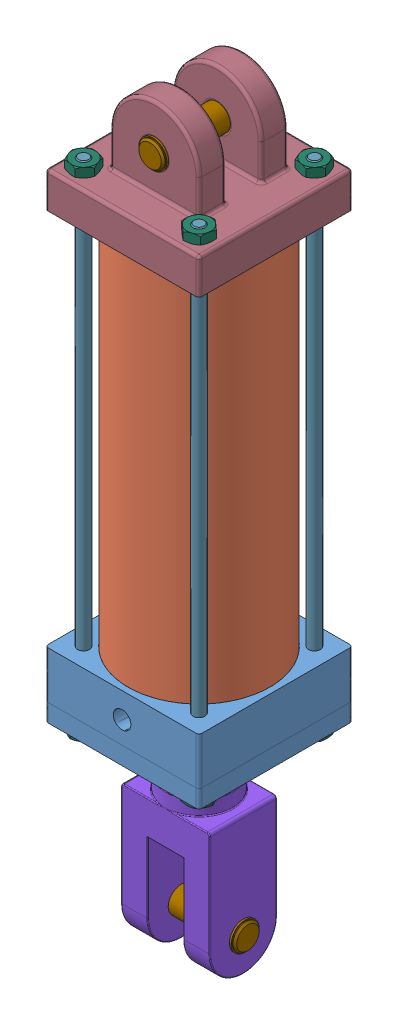
SolidWorks assembly Assem1, configuration Default. Lengths in mm.
Overall size (215.21 810.62 215.21).
28 component instances, 15 part files, 41 mates.
Components (placement in the parent):
- topcover3-2: topcover3 [Default] x (-1 0 0) z (0 1 0) size (165.1 165.1 102.8)
- housingpart-1: housingpart [Default] x (-0.66754 0 0.744574) z (0 1 0) size (152.4 152.4 412)
- backingseal5-1: backingseal5 [Default] at (0 -1 0) x (0 1 0) z (0 0 -1) size (2 152.4 152.4)
- backingseal5-2: backingseal5 [Default] at (0 413 0) x (0 1 0) z (0 0 -1) size (2 152.4 152.4)
- piston seal-1: piston seal [Default] at (0 300.2 0) x (0.999723 0 0.023537) z (0.023537 0 -0.999723) size (146.62 12 146.62)
- piston7-1: piston7 [Default] at (0 318.2 0) x (0 1 0) z (0 0 1) size (57 146.05 146.05)
- pistonrod-1: pistonrod [Default] at (0 -168.8 0) x (0 1 0) z (0.266306 0 0.963889) size (526.03 40 40)
- rod nut-1: rod nut [Default] at (0 318.2 0) x (-0.381849 0 -0.924225) z (0.924225 0 -0.381849) size (61.51 20 61.51)
- fork4-1: fork4 [Default] at (0 -132.8 0) x (0 1 0) z (-1 0 0) size (164 72.28 95.25)
- piston seal-2: piston seal [Default] at (0 279.2 0) x (0.606556 0 -0.79504) z (0.79504 0 0.606556) size (146.62 12 146.62)
- barrate6-1: barrate6 [Default] at (0 -244.8 0) x (1 0 0) z (0 0.998476 0.05519) size (105 30 30)
- rod guide-1: rod guide [Default] at (0 -55.0402 0) x (-0.855583 0 -0.517665) z (0 -1 0) size (60 60 28)
- seal 2-3: seal 2 [Default] at (0 -77.0402 0) x (0.837169 0 0.546944) z (0 -1 0) size (65 65 6)
- guide rod nut-2: guide rod nut [Default] at (0 -116.8 0) x (0.989638 0 -0.143584) z (0 1 0) size (68.32 74.44 43.84)
- lowercap2-1: lowercap2 [Default] at (0 406 0) size (165.1 123.83 165.1)
- tensionbolt-2: tensionbolt [Default] at (-61.9638 187.125 61.9638) x (0 -1 0) z (-0.981992 0 -0.188924) size (536 12.7 12.7)
- tension bolt nut-1: tension bolt nut [Default] at (-61.9638 449.1 61.9638) x (0.944513 0 -0.328474) z (0.328474 0 0.944513) size (25.4 10 29.33)
- tension bolt nut-2: tension bolt nut [Default] at (-61.9638 -74.85 61.9638) size (25.4 10 29.33)
- tension bolt nut-3: tension bolt nut [Default] at (-61.9638 449.1 -61.9638) x (0.328474 0 0.944513) z (-0.944513 0 0.328474) size (25.4 10 29.33)
- tension bolt nut-4: tension bolt nut [Default] at (61.9638 449.1 -61.9638) x (-0.944513 0 0.328474) z (-0.328474 0 -0.944513) size (25.4 10 29.33)
- tension bolt nut-5: tension bolt nut [Default] at (61.9638 449.1 61.9638) x (-0.328474 0 -0.944513) z (0.944513 0 -0.328474) size (25.4 10 29.33)
- tensionbolt-3: tensionbolt [Default] at (-61.9638 187.125 -61.9638) x (0 -1 0) z (0.188924 0 -0.981992) size (536 12.7 12.7)
- tensionbolt-4: tensionbolt [Default] at (61.9638 187.125 -61.9638) x (0 -1 0) z (0.981992 0 0.188924) size (536 12.7 12.7)
- tensionbolt-5: tensionbolt [Default] at (61.9638 187.125 61.9638) x (0 -1 0) z (-0.188924 0 0.981992) size (536 12.7 12.7)
- tension bolt nut-6: tension bolt nut [Default] at (-61.9638 -74.85 -61.9638) x (0 0 1) z (-1 0 0) size (25.4 10 29.33)
- tension bolt nut-7: tension bolt nut [Default] at (61.9638 -74.85 -61.9638) x (-1 0 0) z (0 0 -1) size (25.4 10 29.33)
- tension bolt nut-8: tension bolt nut [Default] at (61.9638 -74.85 61.9638) x (0 0 -1) z (1 0 0) size (25.4 10 29.33)
- barrate6-2: barrate6 [Default] at (0 482.2 0) x (0 0 -1) z (0.312624 -0.949877 0) size (105 30 30)
Mates (geometry in assembly coordinates):
- Concentric1: concentric aligned: cylinder of housingpart-1 through (0 412 0) axis (0 -1 0) radius 69.85; cylinder of backingseal5-2 through (0 414 0) axis (0 -1 0) radius 69.85
- Concentric2: concentric aligned: cylinder of housingpart-1 through (0 412 0) axis (0 -1 0) radius 69.85; cylinder of backingseal5-1 through (0 0 0) axis (0 -1 0) radius 69.85
- Coincident4: coincident anti-aligned: plane of housingpart-1 through (0 0 0) normal (0 -1 0); plane of backingseal5-1 through (0 0 0) normal (0 1 0)
- Concentric3: concentric anti-aligned: cylinder of topcover3-2 through (0 -60.8 0) axis (0 1 0) radius 20; cylinder of housingpart-1 through (0 412 0) axis (0 -1 0) radius 76.2
- Coincident5: coincident anti-aligned: plane of housingpart-1 through (0 412 0) normal (0 1 0); plane of backingseal5-2 through (0 412 0) normal (0 -1 0)
- Coincident6: coincident aligned: circle of topcover3-2; circle of backingseal5-1
- Concentric4: concentric anti-aligned: cylinder of piston7-1 through (0 -265.5511 0) axis (0 -1 0) radius 15; cylinder of pistonrod-1 through (0 -239.2683 0) axis (0 1 0) radius 15
- Coincident7: coincident anti-aligned: plane of piston7-1 through (-66.675 190.7317 0) normal (0 -1 0); plane of pistonrod-1 through (-14.4583 190.7317 3.9946) normal (0 1 0)
- Concentric6: concentric aligned: cylinder of pistonrod-1 through (0 -239.2683 0) axis (0 1 0) radius 15; cylinder of rod nut-1 through (0 267.7317 0) axis (0 1 0) radius 15
- Coincident8: coincident anti-aligned: plane of piston7-1 through (-15 247.7317 0) normal (0 1 0); plane of rod nut-1 through (0 247.7317 0) normal (0 -1 0)
- Concentric7: concentric aligned: cylinder of piston7-1 through (0 -265.5511 0) axis (0 -1 0) radius 73.025; cone of piston seal-2 through (0 214.7317 0) axis (0 -1 0)
- Coincident9: coincident anti-aligned: plane of piston7-1 through (-66.675 202.7317 0) normal (0 1 0); plane of piston seal-2 through (-58.2844 202.7317 -44.4666) normal (0 -1 0)
- Concentric8: concentric anti-aligned: cone of piston seal-1 through (0 223.7317 0) axis (0 1 0); cylinder of piston7-1 through (0 -265.5511 0) axis (0 -1 0) radius 73.025
- Coincident11: coincident anti-aligned: plane of piston seal-1 through (-1.7255 235.7317 73.2897) normal (0 1 0); plane of piston7-1 through (-73.025 235.7317 0) normal (0 -1 0)
- Concentric9: concentric anti-aligned: cylinder of housingpart-1 through (0 412 0) axis (0 -1 0) radius 69.85; cylinder of pistonrod-1 through (0 -239.2683 0) axis (0 1 0) radius 20
- Concentric11: concentric aligned: cylinder of pistonrod-1 through (0 -239.2683 0) axis (0 1 0) radius 15; cylinder of fork4-1 through (0 -187.2683 0) axis (0 1 0) radius 15
- Coincident13: coincident anti-aligned: plane of pistonrod-1 through (-19.2778 -187.2683 5.3261) normal (0 -1 0); plane of fork4-1 through (0 -187.2683 0) normal (0 1 0)
- Coincident14: coincident anti-aligned: plane of pistonrod-1 through (-19.2778 -187.2683 5.3261) normal (0 -1 0); plane of fork4-1 through (0 -187.2683 0) normal (0 1 0)
- Concentric13: concentric anti-aligned: cylinder of fork4-1 through (-47.625 -315.2683 0) axis (1 0 0) radius 12; cylinder of barrate6-1 through (-632.8203 -315.2683 0) axis (-1 0 0) radius 14
- Width1: width aligned: plane of fork4-1 through (-47.625 -203.2683 0) normal (-1 0 0); plane of barrate6-1 through (47.625 -203.2683 0) normal (1 0 0); plane of fork4-1 through (-52.5 -315.2683 0) normal (-1 0 0); plane of barrate6-1 through (52.5 -315.2683 0) normal (1 0 0)
- Parallel2: parallel aligned: plane of topcover3-2 through (82.55 -50.8 0) normal (1 0 0); plane of fork4-1 through (47.625 -203.2683 0) normal (1 0 0)
- Concentric27: concentric aligned: cylinder of rod guide-1 through (0 -83.0402 0) axis (0 1 0) radius 30; cylinder of seal 2-3 through (0 -83.0402 0) axis (0 1 0) radius 30
- Coincident28: coincident aligned: plane of rod guide-1 through (0 -83.0402 0) normal (0 -1 0); plane of seal 2-3 through (0 -83.0402 0) normal (0 -1 0)
- Concentric29: concentric aligned: cylinder of pistonrod-1 through (0 -239.2683 0) axis (0 1 0) radius 20; cylinder of rod guide-1 through (0 -83.0402 0) axis (0 1 0) radius 20
- Concentric30: concentric aligned: cylinder of topcover3-2 through (0 -82.8 0) axis (0 1 0) radius 30; cylinder of rod guide-1 through (0 -83.0402 0) axis (0 1 0) radius 30
- Concentric31: concentric anti-aligned: cylinder of pistonrod-1 through (0 -239.2683 0) axis (0 1 0) radius 20; cylinder of guide rod nut-2 through (0 -102.8 0) axis (0 -1 0) radius 21
- Coincident30: coincident aligned: circle of rod guide-1; cylinder of guide rod nut-2 through (0 -99.8 0) axis (0 -1 0) radius 30
- Coincident31: coincident aligned: plane of topcover3-2 through (82.55 -50.8 0) normal (1 0 0); plane of lowercap2-1 through (82.55 406 82.55) normal (1 0 0)
- Parallel4: parallel aligned: plane of topcover3-2 through (0 -50.8 82.55) normal (0 0 1); plane of lowercap2-1 through (0 406 82.55) normal (0 0 1)
- Coincident33: coincident aligned: plane of topcover3-2 through (0 -50.8 82.55) normal (0 0 1); plane of lowercap2-1 through (0 406 82.55) normal (0 0 1)
- Coincident34: coincident anti-aligned: plane of backingseal5-2 through (0 414 0) normal (0 1 0); plane of lowercap2-1 through (0 414 0) normal (0 -1 0)
- Coincident35: coincident aligned: circle of topcover3-2; cylinder of tensionbolt-2 through (-61.9638 -80.875 61.9638) axis (0 1 0) radius 6.35
- Width3: width anti-aligned: plane of topcover3-2 through (0 -69.85 0) normal (0 -1 0); plane of tensionbolt-2 through (0 444.1 82.55) normal (0 1 0); plane of lowercap2-1 through (-61.9638 -80.875 61.9638) normal (0 -1 0); plane of tensionbolt-2 through (-61.9638 455.125 61.9638) normal (0 1 0)
- Concentric35: concentric anti-aligned: axis of tensionbolt-2 through (-61.9638 -79.875 61.9638) axis (0 1 0); cylinder of tension bolt nut-1 through (-61.9638 454.1 61.9638) axis (0 -1 0) radius 6.35
- Coincident36: coincident anti-aligned: plane of lowercap2-1 through (0 444.1 82.55) normal (0 1 0); plane of tension bolt nut-1 through (-61.9638 444.1 61.9638) normal (0 -1 0)
- Concentric36: concentric anti-aligned: cylinder of tensionbolt-2 through (-61.9638 -80.875 61.9638) axis (0 1 0) radius 6.35; cylinder of tension bolt nut-2 through (-61.9638 -69.85 61.9638) axis (0 -1 0) radius 6.35
- Coincident38: coincident anti-aligned: plane of topcover3-2 through (0 -69.85 0) normal (0 -1 0); plane of tension bolt nut-2 through (-61.9638 -69.85 61.9638) normal (0 1 0)
- Concentric37: concentric anti-aligned: cylinder of lowercap2-1 through (0 482.2 47.625) axis (0 0 -1) radius 12.7; cylinder of barrate6-2 through (0 482.2 632.8203) axis (0 0 1) radius 14
- Width4: width aligned: plane of lowercap2-1 through (0 406 -47.625) normal (0 0 -1); plane of barrate6-2 through (0 406 47.625) normal (0 0 1); plane of lowercap2-1 through (0 482.2 -52.5) normal (0 0 -1); plane of barrate6-2 through (0 482.2 52.5) normal (0 0 1)
- Coincident43: coincident anti-aligned: plane of topcover3-2 through (0 -102.8 0) normal (0 -1 0); plane of guide rod nut-2 through (0 -102.8 0) normal (0 1 0)
- LimitDistance5: limit distance = 0 mm anti-aligned: plane of fork4-1 through (0 -116.8 0) normal (0 1 0); plane of guide rod nut-2 through (0 -116.8 0) normal (0 -1 0)
